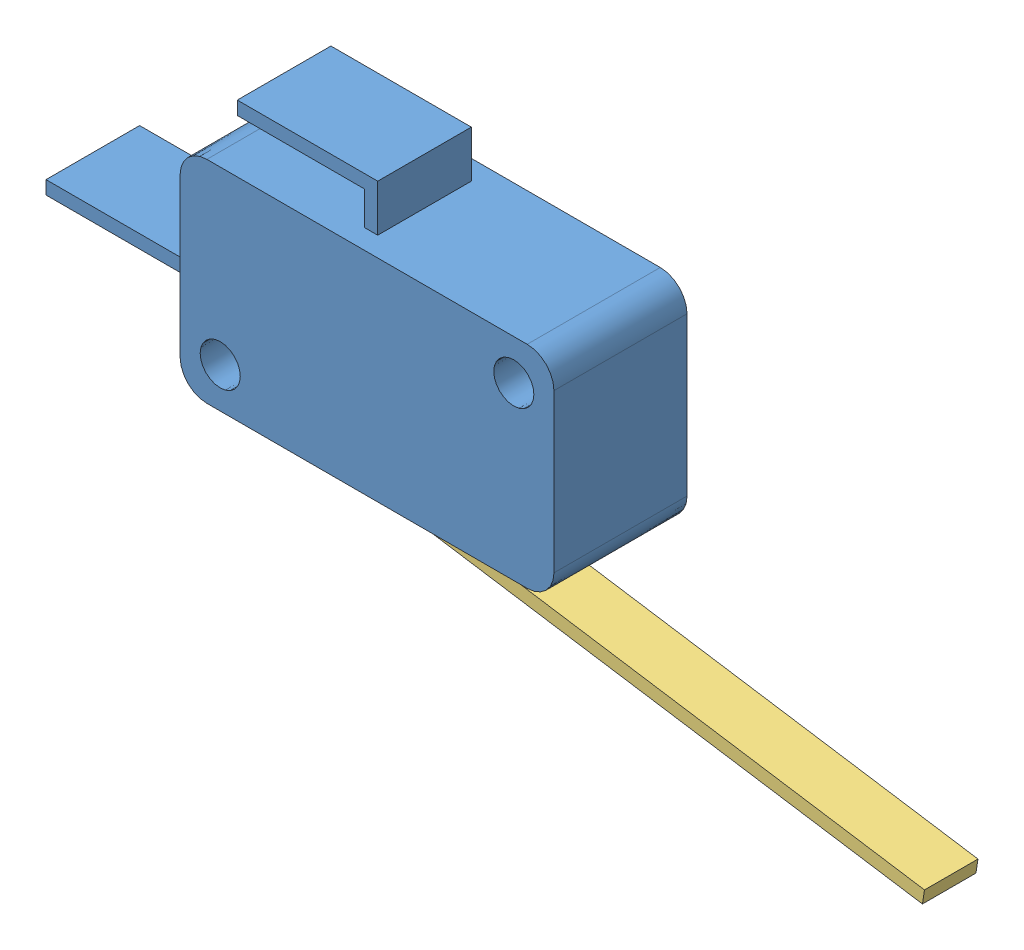
SolidWorks assembly Assem2, configuration Default. Lengths in mm.
Overall size (64.7 27.58 9.95).
3 component instances, 3 part files, 3 mates.
Components (placement in the parent):
- switchbody-1: switchbody [Default] at origin size (39.45 19.3 9.95)
- button-1: button [Default] at (8.275 -4.8104 4.975) x (1 0 0) z (0 -1 0) size (2.6 4 5.6)
- lever-1: lever [Default] at (15.4957 -10.5167 3.3323) x (-0.999858 0.016849 0) z (0 0 1) size (41.75 10.59 4)
Mates (geometry in assembly coordinates):
- Coincident1: coincident anti-aligned: circle of switchbody-1; circle of lever-1
- Coincident2: coincident: plane of switchbody-1 through (9.575 -4.9 2.975) normal (0 0 1); plane of button-1 through (6.975 -10.4104 2.975) normal (0 0 -1)
- Coincident3: coincident anti-aligned: plane of switchbody-1 through (6.975 -4.9 6.975) normal (1 0 0); plane of button-1 through (6.975 -10.4104 6.975) normal (-1 0 0)
